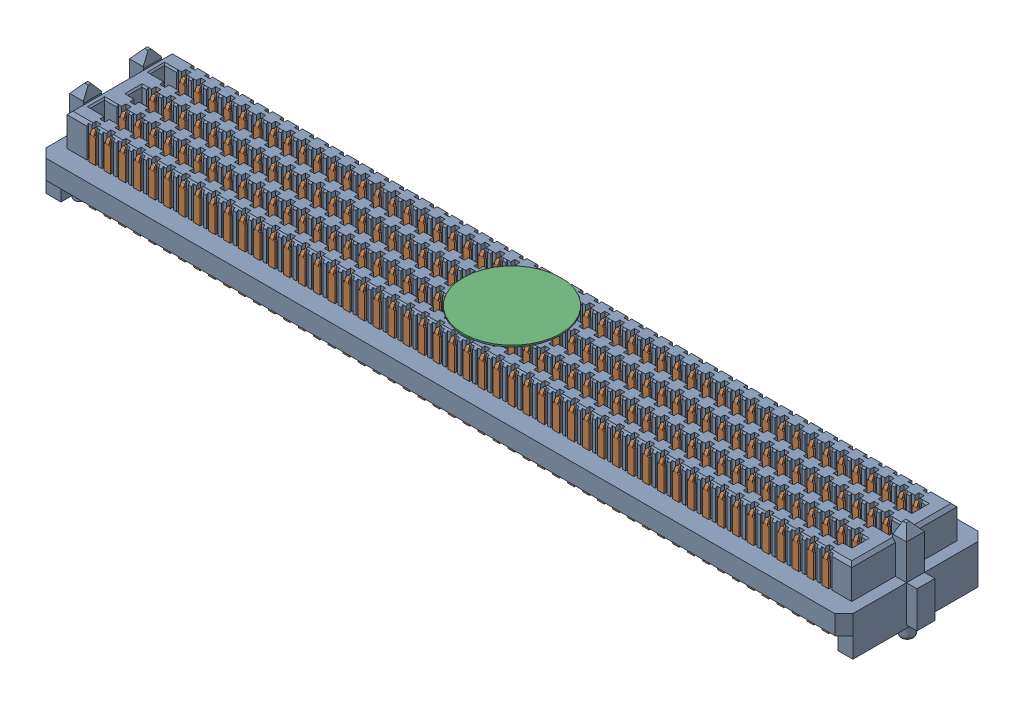
SolidWorks assembly SEAM-50-03.5-S-08-2-A-K-TR, configuration Default. Lengths in mm.
Overall size (69.37 8.38 12.14).
4 component instances, 4 part files, 0 mates.
Components (placement in the parent):
- _SEAM-50-03.5-L-08-1-A-K-TR_body-1: _SEAM-50-03.5-L-08-1-A-K-TR_body [Default] at origin size (69.37 8.38 12.14)
- _SEAM-50-03.5-L-08-1-A-K-TR_conn-1: _SEAM-50-03.5-L-08-1-A-K-TR_conn [Default] at origin size (67.97 5.75 11.63)
- _SEAM_K_Pad_08-1: _SEAM_K_Pad_08 [Default] at (0 2.7432 0) size (8.26 0.13 8.26)
- _SEAM_Triangle-1: _SEAM_Triangle [Default] at (32.2834 1.3462 -4.2164) x (-1 0 0) z (0 0 -1) size (1.02 1.27 0.13)
